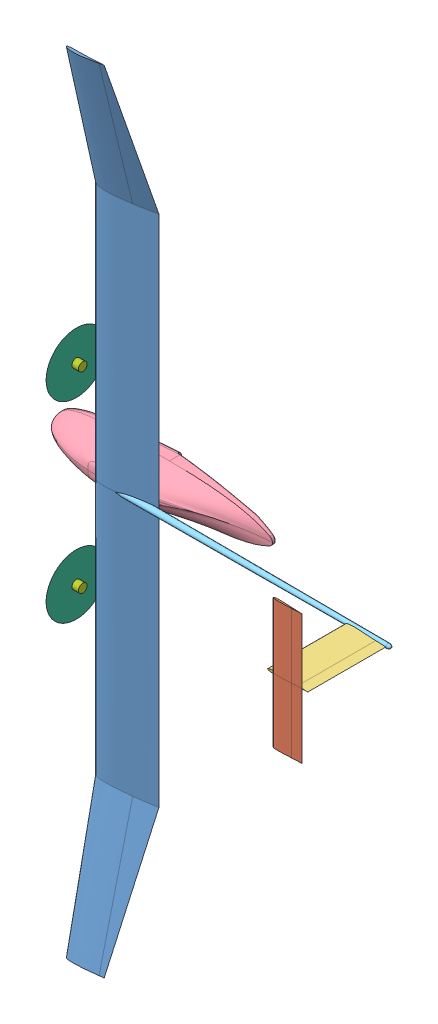
SolidWorks assembly seaway_mini, configuration Default. Lengths in mm.
Overall size (1696.44 3665.18 602.42).
10 component instances, 8 part files, 4 mates.
Components (placement in the parent):
- seaway_mini_lifting_surfaces-1: seaway_mini_lifting_surfaces [Default] at origin size (1354.54 3662.11 391.61)
  - seaway_mini_lifting_surfaces(2)^seaway_mini_lifting_surfaces-1: seaway_mini_lifting_surfaces(2)^seaway_mini_lifting_surfaces [Default] at origin size (1354.54 3662.11 391.61) (virtual)
    - Open CASCADE STEP translator 7.6 1.1^seaway_mini_lifting_surfaces(2)_seaway_mini_lifting_surfaces-1: Open CASCADE STEP translator 7.6 1.1^seaway_mini_lifting_surfaces(2)_seaway_mini_lifting_surfaces [Default] at origin size (287.42 3662.11 191.26)
    - Open CASCADE STEP translator 7.6 1.2^seaway_mini_lifting_surfaces(2)_seaway_mini_lifting_surfaces-1: Open CASCADE STEP translator 7.6 1.2^seaway_mini_lifting_surfaces(2)_seaway_mini_lifting_surfaces [Default] at origin size (133.35 600.04 8.63) (virtual)
    - Open CASCADE STEP translator 7.6 1.3^seaway_mini_lifting_surfaces(2)_seaway_mini_lifting_surfaces-1: Open CASCADE STEP translator 7.6 1.3^seaway_mini_lifting_surfaces(2)_seaway_mini_lifting_surfaces [Default] at origin size (185.74 12.01 371.46) (virtual)
- Pod Only-1: Pod Only [Default] at (-120.6 0 -171.7289) size (999.88 178.1 221.1)
- Boom^seaway_mini-1: Boom^seaway_mini [Default] at origin size (1295.2 30.07 30.07) (virtual)
- Panels^seaway_mini-1: Panels^seaway_mini [Default] at origin size (256.88 1834.05 174.45) (virtual)
- Props^seaway_mini-1: Props^seaway_mini [Default] at origin size (0 1168.4 279.4) (virtual)
- Motors^seaway_mini-1: Motors^seaway_mini [Default] at origin size (30 929 40) (virtual)
Mates (geometry in assembly coordinates):
- Coincident1: coincident aligned: plane of Pod Only-1 through (-120.6 0 -171.7289) normal (0 1 0)
- Distance1: distance = 400 mm: point of assembly; plane of assembly; point of Pod Only-1
- Distance2: distance = 10 mm: unknown of Pod Only-1
- Parallel1: parallel aligned: plane of Pod Only-1 through (-120.6 0 -171.7289) normal (0 0 1)
